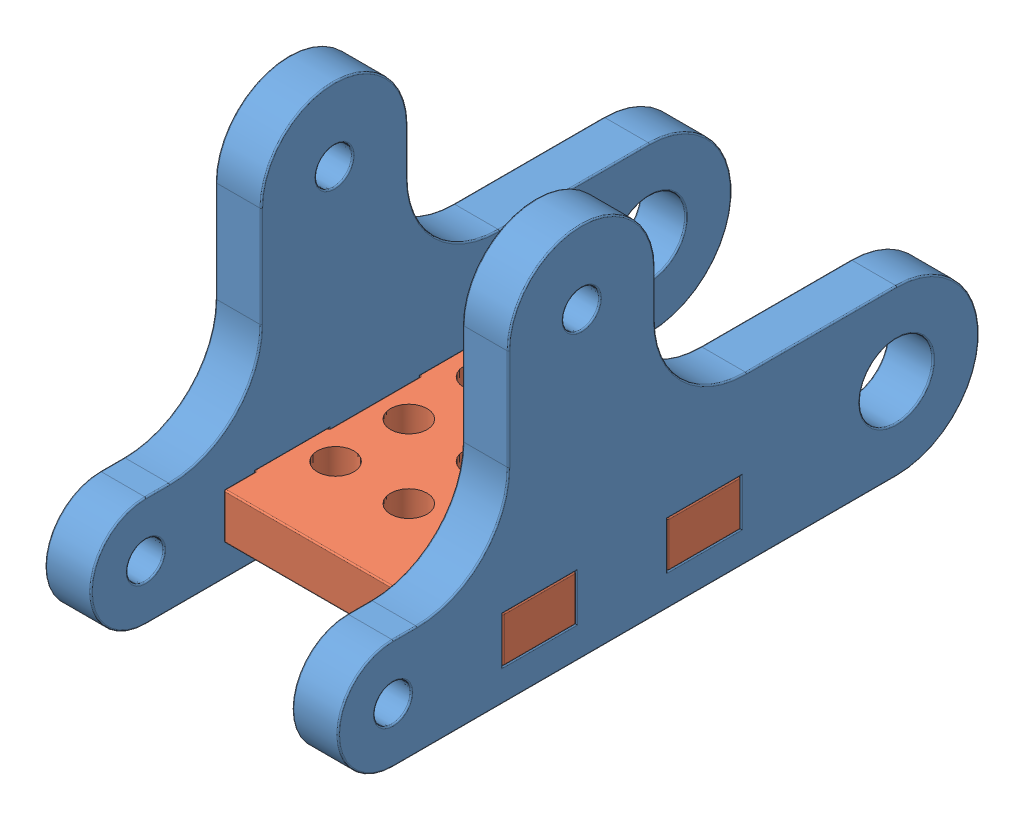
SolidWorks assembly cap assemble, configuration Default. Lengths in mm.
Overall size (39.5 41 70).
3 component instances, 2 part files, 6 mates.
Components (placement in the parent):
- part6 01-1: part6 01 [Domyślna] at (10.3952 20.3277 60.6137) x (0 0 -1) z (1 0 0) size (70 41 10)
- part7 01-2: part7 01 [Domyślna] at (23.8952 26.3277 63.1137) x (0 0 -1) z (0 1 0) size (33 32 5)
- part6 01-2: part6 01 [Domyślna] at (37.3952 20.3277 60.6137) x (0 0 -1) z (1 0 0) size (70 41 10)
Mates (geometry in assembly coordinates):
- Coincident7: coincident: plane of part6 01-1 through (12.8952 28.8277 58.1137) normal (0 -1 0); plane of part7 01-2 through (23.8952 28.8277 63.1137) normal (0 1 0)
- Coincident8: coincident: plane of part6 01-1 through (7.8952 26.3277 88.1137) normal (-1 0 0); plane of part7 01-2 through (7.8952 28.8277 63.1137) normal (-1 0 0)
- Coincident9: coincident: plane of part6 01-1 through (12.8952 28.8277 50.1137) normal (0 0 1); plane of part7 01-2 through (23.8952 28.8277 50.1137) normal (0 0 -1)
- Concentric1: concentric: cylinder of part6 01-1 through (12.8952 26.3277 88.1137) axis (-1 0 0) radius 2; cylinder of part6 01-2 through (39.8952 26.3277 88.1137) axis (-1 0 0) radius 2
- Concentric2: concentric: cylinder of part6 01-1 through (12.8952 29.3277 33.1137) axis (-1 0 0) radius 4; cylinder of part6 01-2 through (39.8952 29.3277 33.1137) axis (-1 0 0) radius 4
- Coincident11: coincident: plane of part7 01-2 through (34.8952 28.8277 63.1137) normal (1 0 0); plane of part6 01-2 through (34.8952 26.3277 88.1137) normal (-1 0 0)
